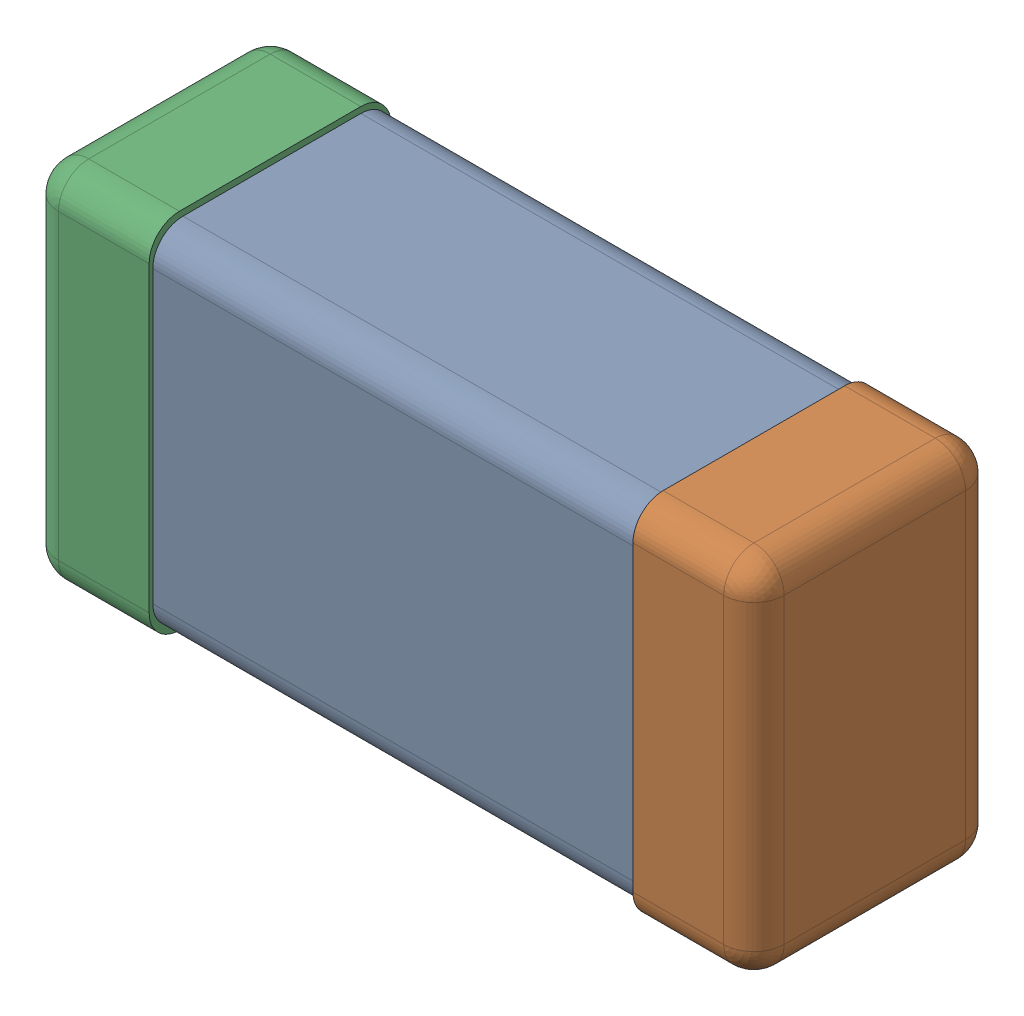
SolidWorks assembly C0201_020_20, configuration Standard. Lengths in mm.
Overall size (0.6 0.3 0.2).
4 component instances, 3 part files, 0 mates.
Components (placement in the parent):
- C0201_020_21-1: C0201_020_21 [Standard] at origin size (0.6 0.3 0.2)
  - Part 3_2-1: Part 3_2 [Standard] at (0 0 -7.3015) size (0.5 0.29 0.2)
  - Part 2_2-1: Part 2_2 [Standard] at (0 0 -7.3) size (0.1 0.3 0.2)
  - Part 1_2-1: Part 1_2 [Standard] at (0 0 -7.3) size (0.1 0.3 0.2)
